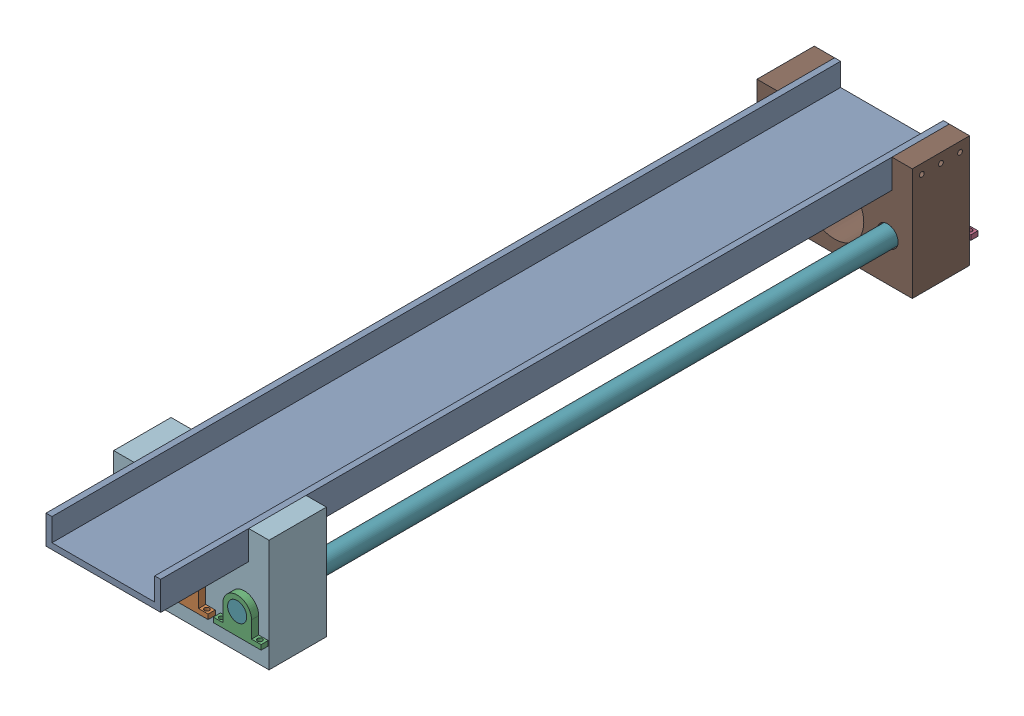
SolidWorks assembly auger assembly, configuration Default. Lengths in mm.
Overall size (65 47 333.83).
13 component instances, 6 part files, 35 mates.
Components (placement in the parent):
- bearing support-1: bearing support [Default] at (607.0821 0 1102.9927) size (20 15 3)
- bearing support-2: bearing support [Default] at (607.0821 0 1399.9927) size (20 15 3)
- bearing support-3: bearing support [Default] at (629.2534 0 1399.9927) size (20 15 3)
- bearing support-4: bearing support [Default] at (629.2534 0 1102.9927) size (20 15 3)
- bearing support-5: bearing support [Default] at (584.9109 0 1102.9927) size (20 15 3)
- bearing support-6: bearing support [Default] at (584.9109 0 1399.9927) size (20 15 3)
- linear motion rod shaft guide 300mm-1: linear motion rod shaft guide 300mm [Default] at (629.2534 9 1102.9927) x (0.956711 -0.291041 0) z (0 0 1) size (8 8 300)
- linear motion rod shaft guide 300mm-2: linear motion rod shaft guide 300mm [Default] at (607.0821 9 1102.9927) x (-0.88519 0.465229 0) z (0 0 1) size (8 8 300)
- linear motion rod shaft guide 300mm-3: linear motion rod shaft guide 300mm [Default] at (584.9109 9 1102.9927) x (0.794316 0.607504 0) z (0 0 1) size (8 8 300)
- nut-1: nut [Default] at (607.0821 9 1109.8221) x (-1 0 0) z (0 1 0) size (22 12 22)
- nutMotorMount-1: nutMotorMount [Default] at (607.0821 9 1106.8221) size (65 47 24)
- part support (not nut)-1: part support (not nut) [Default] at (607.0821 9 1375.9927) size (65 47 24)
- buildplate-1: buildplate [Default] at (607.0821 26.5 1271.8221) x (0 0 -1) z (1 0 0) size (330 12 48)
Mates (geometry in assembly coordinates):
- Coincident1: coincident aligned: line of bearing support-3 through (629.2534 9 1402.9927) axis (0 0 -1); line of linear motion rod shaft guide 300mm-1 through (629.2534 9 1402.9927) axis (0 0 -1)
- Coincident2: coincident aligned: line of bearing support-4 through (629.2534 9 1105.9927) axis (0 0 -1); line of linear motion rod shaft guide 300mm-1 through (629.2534 9 1402.9927) axis (0 0 -1)
- Coincident3: coincident aligned: line of bearing support-1 through (607.0821 9 1105.9927) axis (0 0 -1); line of linear motion rod shaft guide 300mm-2 through (607.0821 9 1402.9927) axis (0 0 -1)
- Coincident4: coincident aligned: line of bearing support-2 through (607.0821 9 1402.9927) axis (0 0 -1); line of linear motion rod shaft guide 300mm-2 through (607.0821 9 1402.9927) axis (0 0 -1)
- Coincident5: coincident aligned: line of bearing support-5 through (584.9109 9 1105.9927) axis (0 0 -1); line of linear motion rod shaft guide 300mm-3 through (584.9109 9 1402.9927) axis (0 0 -1)
- Coincident6: coincident aligned: line of bearing support-6 through (584.9109 9 1402.9927) axis (0 0 -1); line of linear motion rod shaft guide 300mm-3 through (584.9109 9 1402.9927) axis (0 0 -1)
- Parallel1: parallel aligned: line of linear motion rod shaft guide 300mm-1 through (629.2534 9 1402.9927) axis (0 0 -1); line of linear motion rod shaft guide 300mm-2 through (607.0821 9 1402.9927) axis (0 0 -1)
- Parallel2: parallel aligned: line of linear motion rod shaft guide 300mm-2 through (607.0821 9 1402.9927) axis (0 0 -1); line of linear motion rod shaft guide 300mm-3 through (584.9109 9 1402.9927) axis (0 0 -1)
- Coincident9: coincident aligned: line of linear motion rod shaft guide 300mm-2 through (607.0821 9 1402.9927) axis (0 0 -1); line of nut-1 through (607.0821 9 1121.8221) axis (0 0 -1)
- Coincident12: coincident anti-aligned: plane of bearing support-1 through (607.0821 0 1105.9927) normal (0 -1 0)
- Coincident13: coincident anti-aligned: plane of bearing support-3 through (629.2534 0 1402.9927) normal (0 -1 0)
- Coincident14: coincident anti-aligned: plane of bearing support-5 through (584.9109 0 1105.9927) normal (0 -1 0)
- Coincident15: coincident anti-aligned: plane of bearing support-6 through (584.9109 0 1402.9927) normal (0 -1 0)
- Coincident16: coincident anti-aligned: plane of bearing support-2 through (607.0821 0 1402.9927) normal (0 -1 0)
- Coincident17: coincident anti-aligned: plane of bearing support-4 through (629.2534 0 1105.9927) normal (0 -1 0)
- Coincident18: coincident aligned: plane of bearing support-4 through (629.2534 0 1102.9927) normal (0 0 -1); plane of linear motion rod shaft guide 300mm-1 through (629.2534 9 1102.9927) normal (0 0 -1)
- Coincident19: coincident aligned: plane of bearing support-1 through (607.0821 0 1102.9927) normal (0 0 -1); plane of linear motion rod shaft guide 300mm-2 through (607.0821 9 1102.9927) normal (0 0 -1)
- Coincident20: coincident aligned: plane of bearing support-5 through (584.9109 0 1102.9927) normal (0 0 -1); plane of linear motion rod shaft guide 300mm-3 through (584.9109 9 1102.9927) normal (0 0 -1)
- Coincident21: coincident aligned: plane of bearing support-3 through (629.2534 0 1402.9927) normal (0 0 1); plane of linear motion rod shaft guide 300mm-1 through (629.2534 9 1402.9927) normal (0 0 1)
- Coincident22: coincident aligned: plane of bearing support-2 through (607.0821 0 1402.9927) normal (0 0 1); plane of linear motion rod shaft guide 300mm-2 through (607.0821 9 1402.9927) normal (0 0 1)
- Coincident23: coincident aligned: plane of bearing support-6 through (584.9109 0 1402.9927) normal (0 0 1); plane of linear motion rod shaft guide 300mm-3 through (584.9109 9 1402.9927) normal (0 0 1)
- Coincident24: coincident aligned: line of linear motion rod shaft guide 300mm-3 through (584.9109 9 1402.9927) axis (0 0 -1); line of nutMotorMount-1 through (584.9109 9 1130.8221) axis (0 0 -1)
- Coincident25: coincident aligned: line of linear motion rod shaft guide 300mm-2 through (607.0821 9 1402.9927) axis (0 0 -1); line of nutMotorMount-1 through (607.0821 9 1130.8221) axis (0 0 -1)
- Coincident26: coincident aligned: line of linear motion rod shaft guide 300mm-1 through (629.2534 9 1402.9927) axis (0 0 -1); line of nutMotorMount-1 through (629.2534 9 1130.8221) axis (0 0 -1)
- Coincident27: coincident aligned: plane of nut-1 through (607.0821 9 1111.8221) normal (0 0 1); plane of nutMotorMount-1 through (607.0821 9 1111.8221) normal (0 0 1)
- Coincident28: coincident aligned: line of nut-1 through (607.0821 17 1111.8221) axis (0 0 -1); line of nutMotorMount-1 through (607.0821 17 1111.8221) axis (0 0 -1)
- Parallel4: parallel aligned: line of linear motion rod shaft guide 300mm-1 through (629.2534 9 1402.9927) axis (0 0 -1); line of linear motion rod shaft guide 300mm-3 through (584.9109 9 1402.9927) axis (0 0 -1)
- Coincident31: coincident aligned: line of linear motion rod shaft guide 300mm-3 through (584.9109 9 1402.9927) axis (0 0 -1); line of part support (not nut)-1 through (584.9109 9 1399.9927) axis (0 0 -1)
- Coincident32: coincident aligned: line of linear motion rod shaft guide 300mm-1 through (629.2534 9 1402.9927) axis (0 0 -1); line of part support (not nut)-1 through (629.2534 9 1399.9927) axis (0 0 -1)
- Coincident33: coincident aligned: plane of bearing support-2 through (607.0821 0 1402.9927) normal (0 0 1); plane of bearing support-6 through (584.9109 0 1402.9927) normal (0 0 1)
- Coincident34: coincident aligned: plane of bearing support-2 through (607.0821 0 1402.9927) normal (0 0 1); plane of bearing support-3 through (629.2534 0 1402.9927) normal (0 0 1)
- Coincident35: coincident anti-aligned: plane of bearing support-2 through (607.0821 0 1399.9927) normal (0 0 -1); plane of part support (not nut)-1 through (607.0821 9 1399.9927) normal (0 0 1)
- Coincident36: coincident anti-aligned: plane of nutMotorMount-1 through (631.0821 26.5 1130.8221) normal (-1 0 0); plane of buildplate-1 through (631.0821 38.5 1436.8221) normal (1 0 0)
- Coincident37: coincident aligned: plane of nutMotorMount-1 through (607.0821 9 1106.8221) normal (0 0 -1); plane of buildplate-1 through (583.0821 38.5 1106.8221) normal (0 0 -1)
- Coincident38: coincident anti-aligned: plane of nutMotorMount-1 through (607.0821 26.5 1130.8221) normal (0 1 0); plane of buildplate-1 through (607.0821 26.5 1271.8221) normal (0 -1 0)
